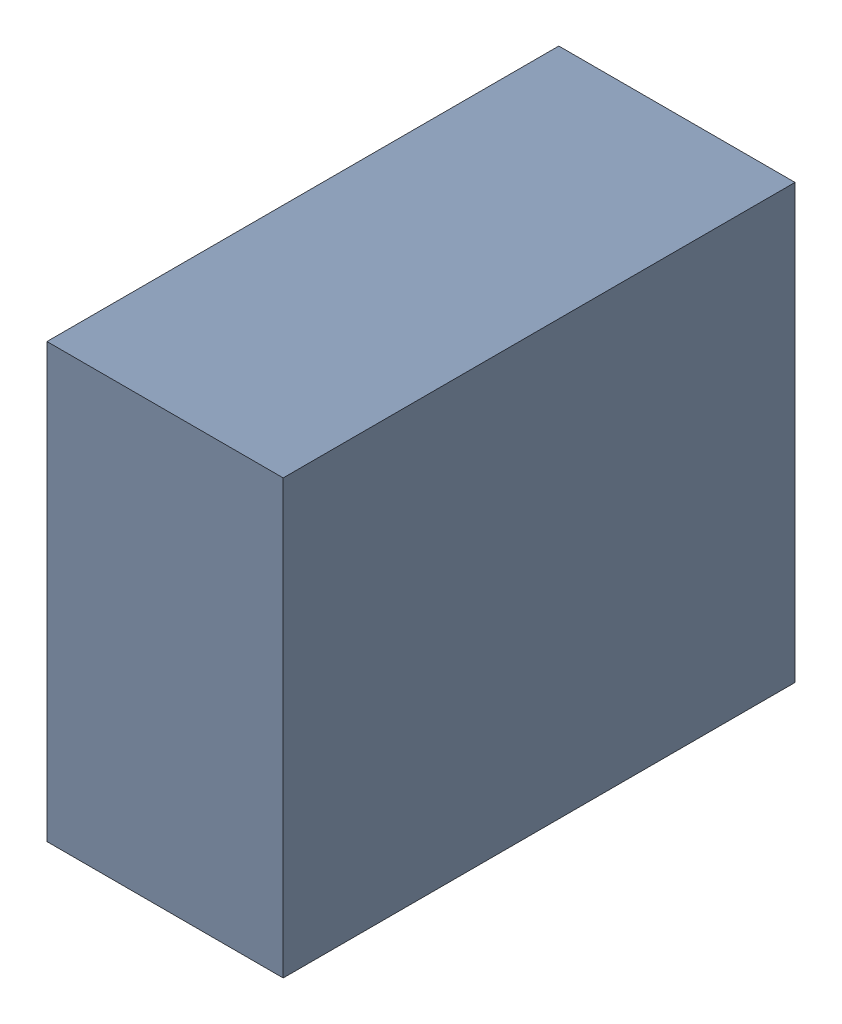
SolidWorks assembly C8, configuration Standard. Lengths in mm.
Overall size (0.6 1.1 1.3).
2 component instances, 1 part files, 0 mates.
Components (placement in the parent):
- 885542376-1: 885542376 [Standard] at (-4.55 13 0) size (0.6 1.1 1.3)
  - Extruded_25-1: Extruded_25 [Standard] at origin size (0.6 1.1 1.3)
